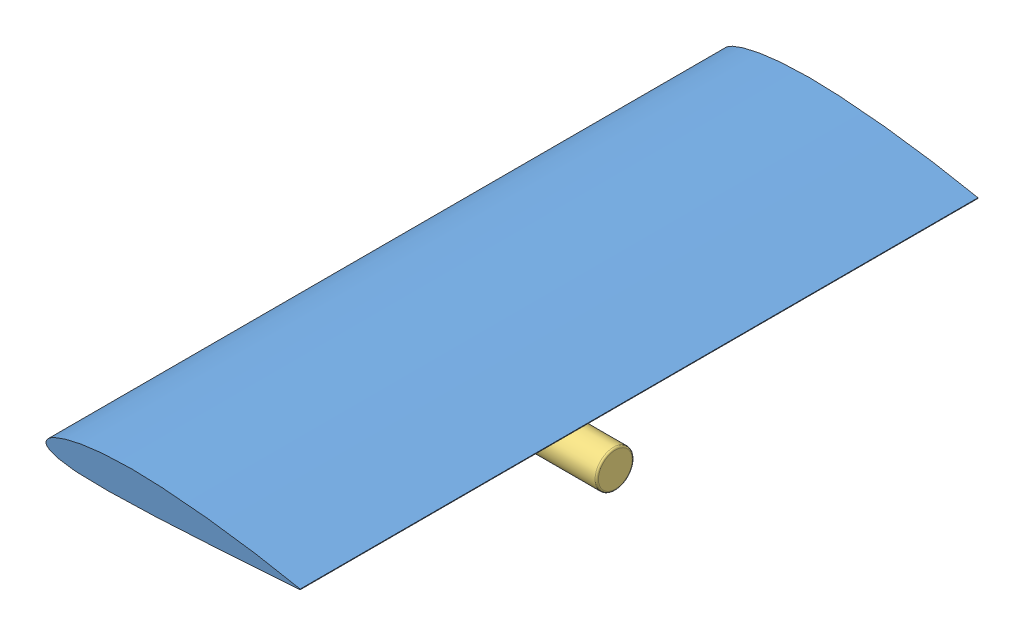
SolidWorks assembly Montagem VF, configuration Valor predeterminado. Lengths in mm.
Overall size (1910.13 707.55 4000).
4 component instances, 4 part files, 9 mates.
Components (placement in the parent):
- Asa Nova-1: Asa Nova [Valor predeterminado] at (-576.5372 -46.554 4000) size (1500.98 182.65 4000)
- Plataforma de Integração Nova-1: Plataforma de Integração Nova [Valor predeterminado] at (23.4628 -329.0017 4000) x (0 0 1) z (0 1 0) size (362.86 853.04 263.47)
- Lancador Novo-1: Lancador Novo [Valor predeterminado] at (783.4628 -504.0017 4000) x (0 0 1) z (-1 0 0) size (220 285 1550)
- Ponta Aerodinâmica Nova-1: Ponta Aerodinâmica Nova [Valor predeterminado] at (-766.5372 -504.0017 4000) x (0 0.215172 -0.976576) z (0 0.976576 0.215172) size (220 220 220)
Mates (geometry in assembly coordinates):
- Coincidente1: coincident aligned: plane of Asa Nova-1 through (-576.5372 -46.554 4000) normal (0 0 1); plane of Plataforma de Integração Nova-1 through (23.4628 -329.0017 4000) normal (0 0 1)
- Distância1: distance = 600 mm aligned: plane of Asa Nova-1 through (-576.5372 -46.554 4000) normal (1 0 0); plane of Plataforma de Integração Nova-1 through (23.4628 -329.0017 4000) normal (1 0 0)
- Coincidente3: coincident anti-aligned: plane of Plataforma de Integração Nova-1 through (273.4628 -329.0017 4000) normal (0 -1 0); plane of Lancador Novo-1 through (183.4628 -329.0017 4000) normal (0 1 0)
- Coincidente5: coincident aligned: plane of Asa Nova-1 through (-576.5372 -46.554 4000) normal (0 0 1); plane of Lancador Novo-1 through (783.4628 -504.0017 4000) normal (0 0 1)
- Distância2: distance = 760 mm anti-aligned: plane of Lancador Novo-1 through (783.4628 -504.0017 4000) normal (-1 0 0); plane of Plataforma de Integração Nova-1 through (23.4628 -329.0017 4000) normal (1 0 0)
- Distância3: distance = 282.4477 mm anti-aligned: plane of Asa Nova-1 through (-576.5372 -46.554 4000) normal (0 1 0); plane of Plataforma de Integração Nova-1 through (273.4628 -329.0017 4000) normal (0 -1 0)
- Coincidente9: coincident anti-aligned: plane of Lancador Novo-1 through (-766.5372 -504.0017 4000) normal (-1 0 0); plane of Ponta Aerodinâmica Nova-1 through (-766.5372 -504.0017 4000) normal (1 0 0)
- Coincidente10: coincident: plane of Lancador Novo-1 through (783.4628 -504.0017 4000) normal (0 1 0); point of Ponta Aerodinâmica Nova-1
- Coincidente11: coincident: plane of Lancador Novo-1 through (783.4628 -504.0017 4000) normal (0 0 1); point of Ponta Aerodinâmica Nova-1
